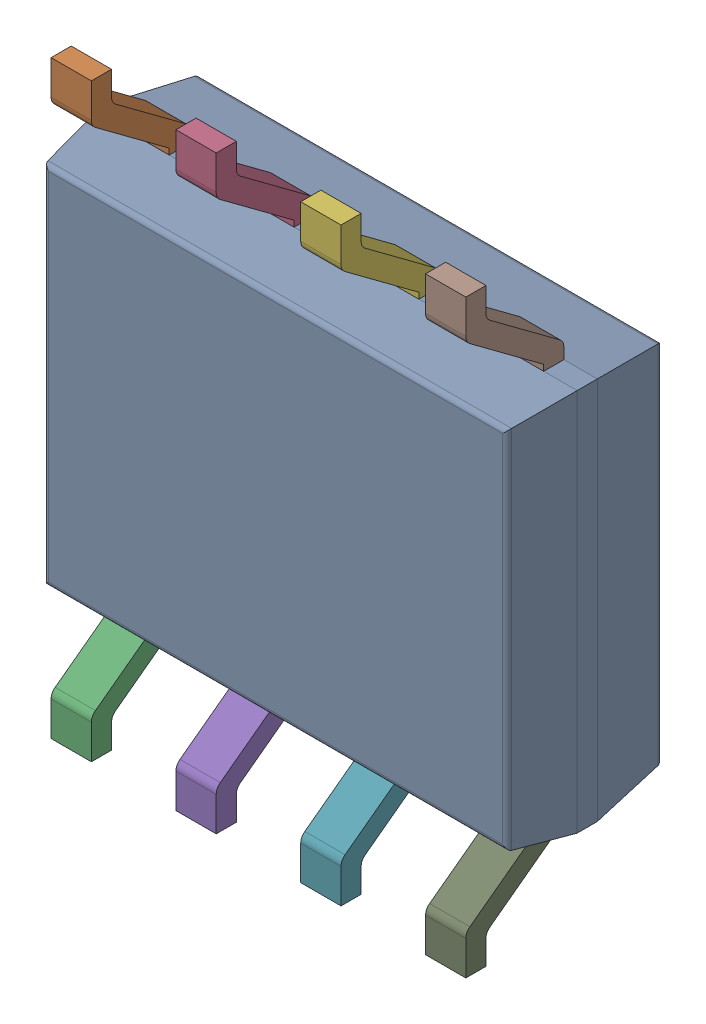
SolidWorks assembly IC1_3.step, configuration Default. Lengths in mm.
Overall size (4.9 6 1.75).
3 component instances, 2 part files, 0 mates.
Components (placement in the parent):
- 12042009920.step-1: 12042009920.step [Default] at (124.46 94.742 -1.0914) x (0 -1 0) z (0 0 -1) size (6 4.9 1.75)
  - Body_5.step-11: Body_5.step [Default] at origin size (3.9 4.9 1.57)
  - PinsArrayLR_3.step-11: PinsArrayLR_3.step [Default] at origin size (6 4.22 1)
